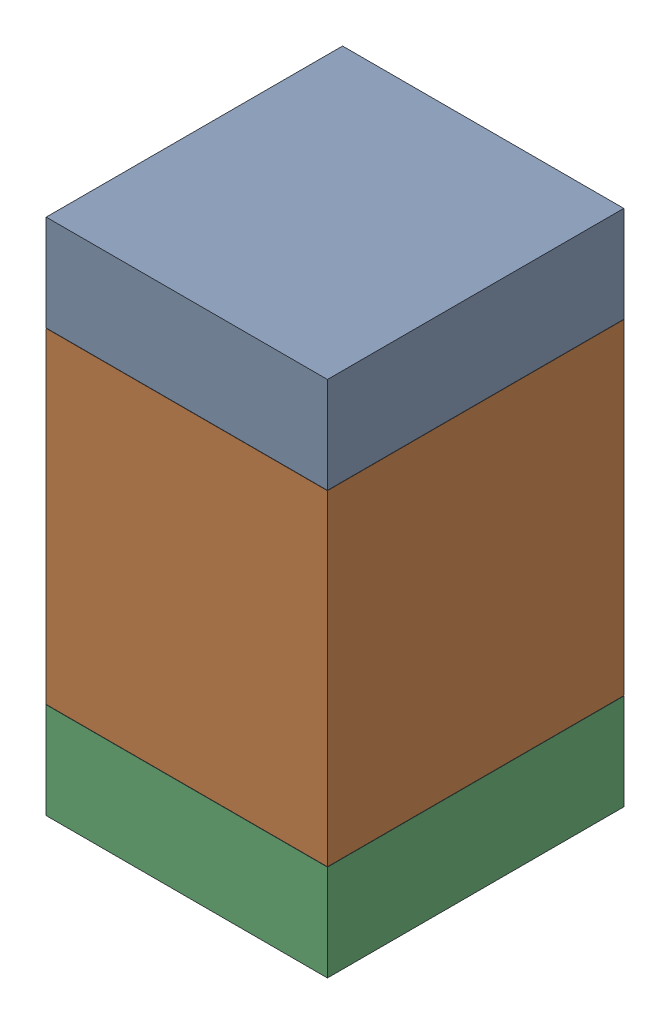
SolidWorks assembly R7, configuration Default. Lengths in mm.
Overall size (0.95 1.75 1).
6 component instances, 2 part files, 0 mates.
Components (placement in the parent):
- 6575495072-1: 6575495072 [Default] at (1.651 27.1285 0) size (0.95 0.32 1)
  - Extruded_6-1: Extruded_6 [Default] at origin size (0.95 0.32 1)
- 6575494912-1: 6575494912 [Default] at (1.651 26.416 0) size (0.95 1.1 1)
  - Extruded_7-1: Extruded_7 [Default] at origin size (0.95 1.1 1)
- 6575495072-2: 6575495072 [Default] at (1.651 25.7035 0) size (0.95 0.32 1)
  - Extruded_6-1: Extruded_6 [Default] at origin size (0.95 0.32 1)
